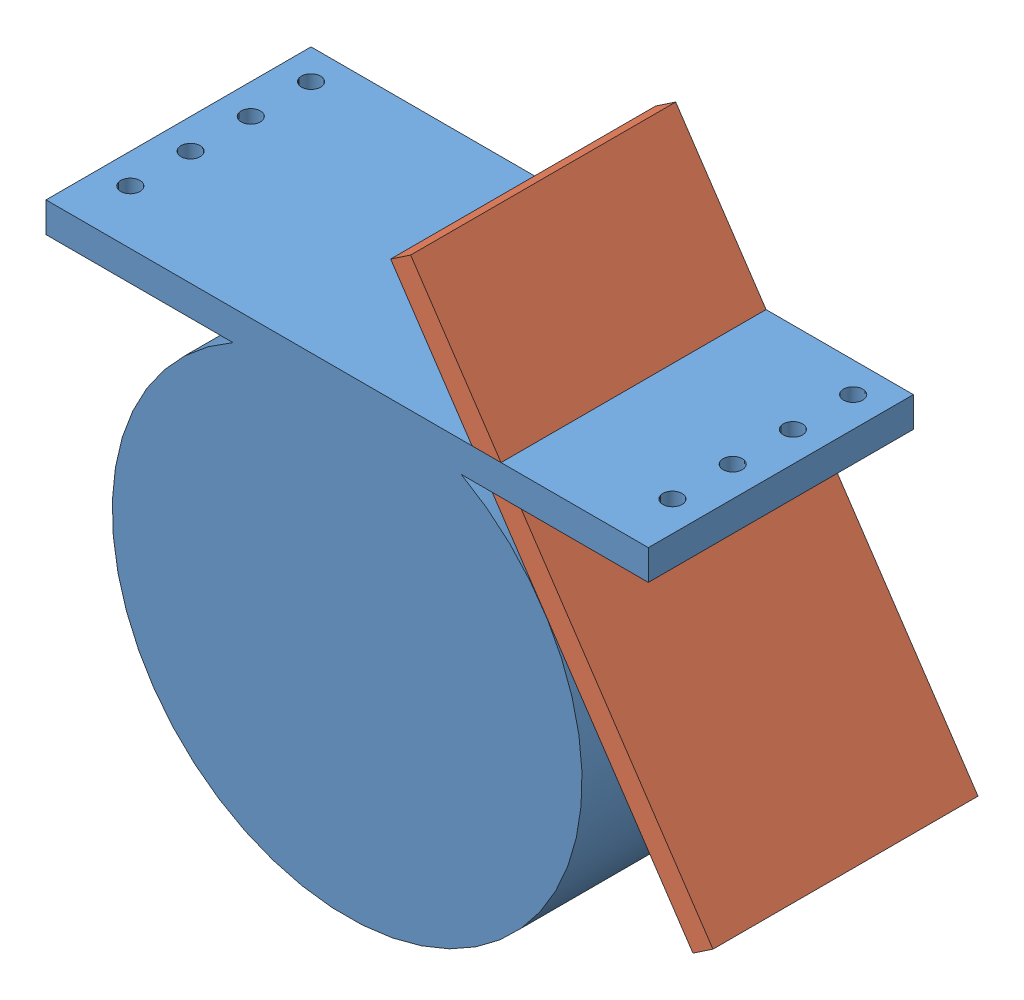
SolidWorks assembly spray_mount_under, configuration ﾃﾞﾌｫﾙﾄ. Lengths in mm.
Overall size (110.73 100.42 44).
2 component instances, 2 part files, 2 mates.
Components (placement in the parent):
- spray_undermount(cup)-1: spray_undermount(cup) [ﾃﾞﾌｫﾙﾄ] at (7.7447 5.3098 52) size (100 78.09 44)
- spray_undermount(board)-1: spray_undermount(board) [ﾃﾞﾌｫﾙﾄ] at (30.5239 36.8976 75.2366) x (0.557649 -0.830077 0) z (0.830077 0.557649 0) size (90 44 4)
Mates (geometry in assembly coordinates):
- 正接1: tangent anti-aligned: cylinder of spray_undermount(cup)-1 through (1.9493 9.4952 96) axis (0 0 -1) radius 39; plane of spray_undermount(board)-1 through (30.5239 36.8976 75.2366) normal (-0.830077 -0.557649 0)
- 一致1: coincident aligned: plane of spray_undermount(cup)-1 through (1.9493 9.4952 52) normal (0 0 -1); plane of spray_undermount(board)-1 through (12.4876 70.9181 52) normal (0 0 -1)
